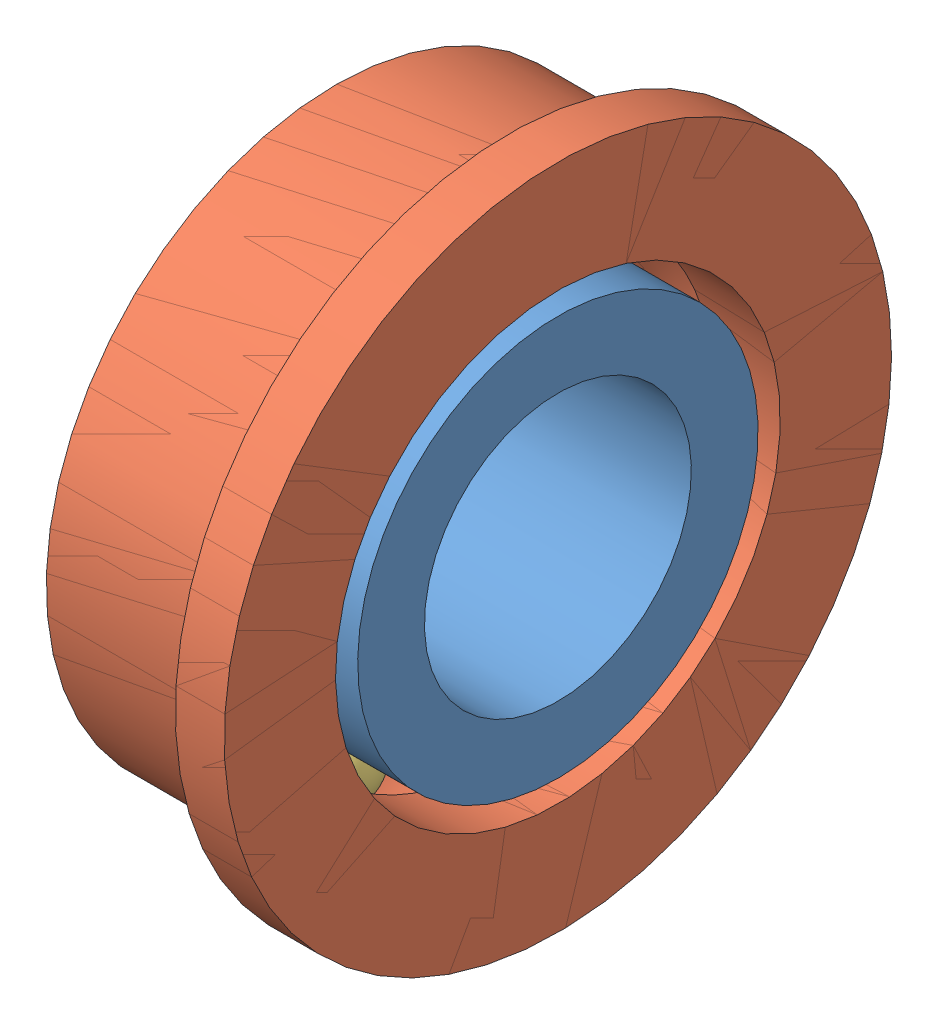
SolidWorks assembly Ball Bearing, configuration Default. Lengths in mm.
Overall size (5 19.82 19.82).
8 component instances, 3 part files, 3 mates.
Components (placement in the parent):
- Inner Ring-1: Inner Ring [Default] at (21.1242 -4.8337 -16.7008) x (1 0 0) z (0 0.704634 -0.709571) size (5 9 9)
- Outer Ring-1: Outer Ring [Default] at (11.2954 13.3679 -15.868) x (1 0 0) z (0 0.409068 0.912504) size (5 15 15)
- Ball-1: Ball [Default] at (-6.3192 1.0157 -15.2392) x (0.843928 -0.345359 -0.410502) z (-0.316384 -0.938387 0.139037) size (2 2 2)
- Ball-14: Ball [Default] at (-6.3192 -2.8893 -12.5349) x (0.843928 -0.528185 0.093839) z (-0.316384 -0.348784 0.882185) size (2 2 2)
- Ball-15: Ball [Default] at (-6.3192 -2.4998 -7.8009) x (0.843928 -0.182826 0.504341) z (-0.316384 0.589603 0.743148) size (2 2 2)
- Ball-16: Ball [Default] at (-6.3192 1.7948 -5.7712) x (0.843928 0.345359 0.410502) z (-0.316384 0.938387 -0.139037) size (2 2 2)
- Ball-17: Ball [Default] at (-6.3192 5.6998 -8.4756) x (0.843928 0.528185 -0.093839) z (-0.316384 0.348784 -0.882185) size (2 2 2)
- Ball-18: Ball [Default] at (-6.3192 5.3103 -13.2096) x (0.843928 0.182826 -0.504341) z (-0.316384 -0.589603 -0.743148) size (2 2 2)
Mates (geometry in assembly coordinates):
- Tangent1: tangent: torus of Inner Ring-1; sphere of Ball-1
- Tangent2: tangent: torus of Outer Ring-1; torus of ?; torus of ?; torus of ?; sphere of Ball-1
- Tangent3: tangent: torus of Outer Ring-1; torus of ?; torus of ?; torus of ?; sphere of Ball-17
